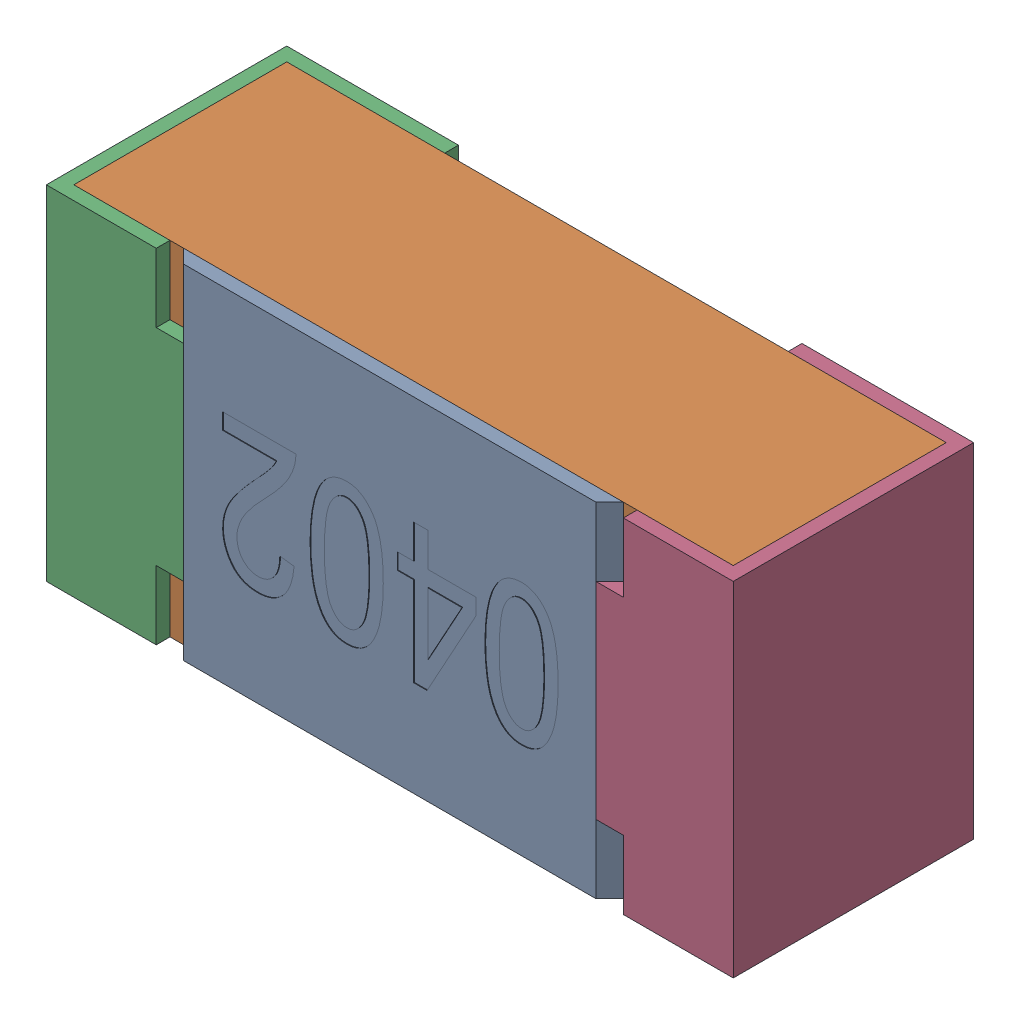
SolidWorks assembly R35, configuration Standard. Lengths in mm.
Overall size (1 0.5 0.35).
5 component instances, 4 part files, 0 mates.
Components (placement in the parent):
- R35-subassembly-1-1: R35-subassembly-1 [Standard] at (5.8999 5.5 0) x (-1 0 0) z (0 0 1) size (1 0.5 0.35)
  - User Library-R_0402-1: User Library-R_0402 [Standard] at origin size (0.64 0.5 0.02)
  - User Library-R_0402-1-1: User Library-R_0402-1 [Standard] at origin size (0.96 0.5 0.31)
  - User Library-R_0402-2-1: User Library-R_0402-2 [Standard] at origin size (0.25 0.5 0.35)
  - User Library-R_0402-3-1: User Library-R_0402-3 [Standard] at origin size (0.25 0.5 0.35)
